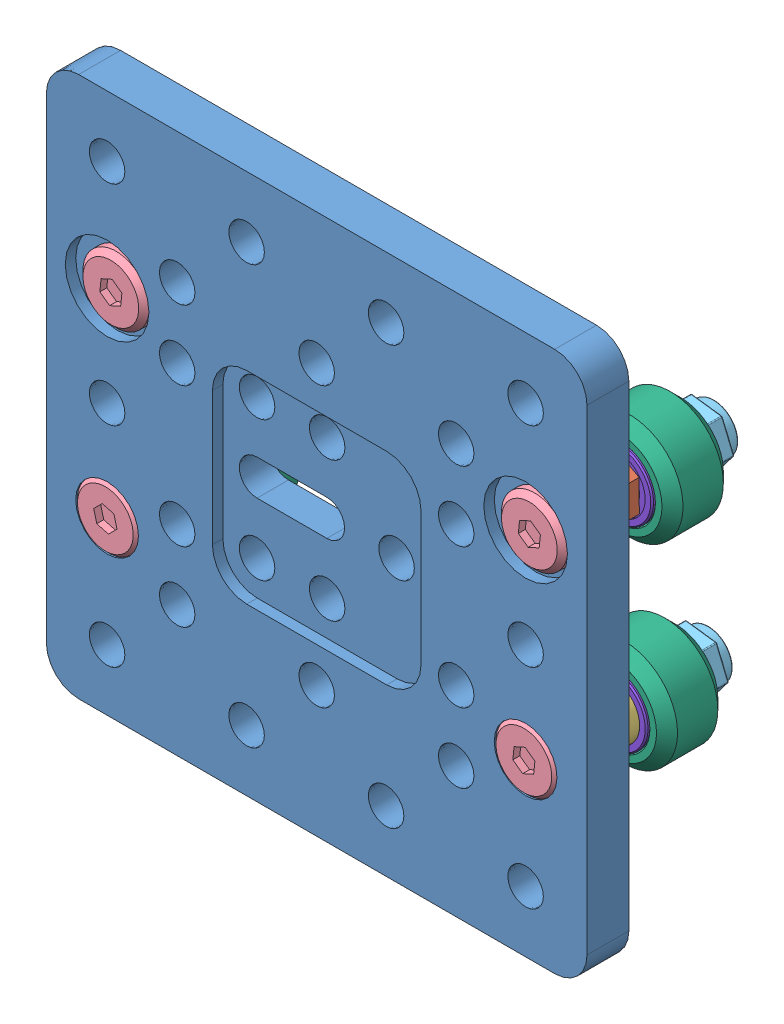
SolidWorks assembly gantry assem, configuration Default. Lengths in mm.
Overall size (77.51 77.52 27.2).
33 component instances, 8 part files, 23 mates.
Components (placement in the parent):
- cb gantry plate-1: cb gantry plate [Default] at (32.7768 44.1711 51.95) size (77.51 77.52 6)
- Steel Eccentric Spacer-1: Steel Eccentric Spacer [Default] at (2.7268 58.4216 51.95) x (0 0 -1) z (1 0 0) size (7.62 9.09 7.9)
- .25 Inch Aluminum Spacer-1: .25 Inch Aluminum Spacer [Default] at (62.7268 29.9216 45.6) x (0 0 1) z (-0.46796 0.88375 0) size (6.35 8 8)
- Steel Eccentric Spacer-2: Steel Eccentric Spacer [Default] at (62.7268 58.4216 51.95) x (0 0 -1) z (1 0 0) size (7.62 9.09 7.9)
- .25 Inch Aluminum Spacer-2: .25 Inch Aluminum Spacer [Default] at (2.7268 29.9216 45.6) x (0 0 1) z (-0.46796 0.88375 0) size (6.35 8 8)
- 5mm Low Profile Socket Head Screw - Multiple Lengths-1: 5mm Low Profile Socket Head Screw - Multiple Lengths [Default] at (62.7268 29.9216 58.2) x (0 0 -1) z (0.994788 -0.101967 0) size (27.2 9.5 9.5)
- 5mm Low Profile Socket Head Screw - Multiple Lengths-2: 5mm Low Profile Socket Head Screw - Multiple Lengths [Default] at (63.5168 58.4216 58.2) x (0 0 -1) z (0.994788 -0.101967 0) size (27.2 9.5 9.5)
- 5mm Low Profile Socket Head Screw - Multiple Lengths-3: 5mm Low Profile Socket Head Screw - Multiple Lengths [Default] at (3.5168 58.4216 58.2) x (0 0 -1) z (0.994788 -0.101967 0) size (27.2 9.5 9.5)
- 5mm Low Profile Socket Head Screw - Multiple Lengths-4: 5mm Low Profile Socket Head Screw - Multiple Lengths [Default] at (2.7268 29.9216 58.2) x (0 0 -1) z (0.966493 0.256693 0) size (27.2 9.5 9.5)
- Nylon Insert Hex Locknut 5mm-1: Nylon Insert Hex Locknut 5mm [Default] at (3.5168 58.4216 36.2) x (-0.923728 -0.383049 0) z (0 0 -1) size (7.68 8.82 4.5)
- Nylon Insert Hex Locknut 5mm-2: Nylon Insert Hex Locknut 5mm [Default] at (62.7268 29.9216 36.2) x (-0.923728 -0.383049 0) z (0 0 -1) size (7.68 8.82 4.5)
- Nylon Insert Hex Locknut 5mm-3: Nylon Insert Hex Locknut 5mm [Default] at (63.5168 58.4216 36.2) x (-0.923728 -0.383049 0) z (0 0 -1) size (7.68 8.82 4.5)
- Nylon Insert Hex Locknut 5mm-4: Nylon Insert Hex Locknut 5mm [Default] at (2.7268 29.9216 36.2) x (-0.923728 -0.383049 0) z (0 0 -1) size (7.68 8.82 4.5)
- MINI WHEEL ASSEM-1: MINI WHEEL ASSEM [Default] at (58.81 21.8771 28.3423) size (15.23 15.23 9.4)
  - Delrin Micro V-Wheel-1: Delrin Micro V-Wheel [Default] at (3.9169 8.0444 12.5577) size (15.23 15.23 8.8)
  - Micro V Precision Shim-1: Micro V Precision Shim [Default] at (3.9169 8.0444 12.0577) x (0 0 1) z (-1 0 0) size (1 8 8)
  - Mini Ball Bearing-3: Mini Ball Bearing [Default] at (3.9169 8.0444 9.9577) x (0 0 1) z (-1 0 0) size (4.2 10 10)
  - Mini Ball Bearing-4: Mini Ball Bearing [Default] at (3.9169 8.0444 15.1577) x (0 0 -1) z (0.923728 0.383049 0) size (4.2 10 10)
- MINI WHEEL ASSEM-2: MINI WHEEL ASSEM [Default] at (59.6 50.3771 28.3423) size (15.23 15.23 9.4)
  - Delrin Micro V-Wheel-1: Delrin Micro V-Wheel [Default] at (3.9169 8.0444 12.5577) size (15.23 15.23 8.8)
  - Micro V Precision Shim-1: Micro V Precision Shim [Default] at (3.9169 8.0444 12.0577) x (0 0 1) z (-1 0 0) size (1 8 8)
  - Mini Ball Bearing-3: Mini Ball Bearing [Default] at (3.9169 8.0444 9.9577) x (0 0 1) z (-1 0 0) size (4.2 10 10)
  - Mini Ball Bearing-4: Mini Ball Bearing [Default] at (3.9169 8.0444 15.1577) x (0 0 -1) z (0.923728 0.383049 0) size (4.2 10 10)
- MINI WHEEL ASSEM-3: MINI WHEEL ASSEM [Default] at (-1.19 21.8771 28.3423) size (15.23 15.23 9.4)
  - Delrin Micro V-Wheel-1: Delrin Micro V-Wheel [Default] at (3.9169 8.0444 12.5577) size (15.23 15.23 8.8)
  - Micro V Precision Shim-1: Micro V Precision Shim [Default] at (3.9169 8.0444 12.0577) x (0 0 1) z (-1 0 0) size (1 8 8)
  - Mini Ball Bearing-3: Mini Ball Bearing [Default] at (3.9169 8.0444 9.9577) x (0 0 1) z (-1 0 0) size (4.2 10 10)
  - Mini Ball Bearing-4: Mini Ball Bearing [Default] at (3.9169 8.0444 15.1577) x (0 0 -1) z (0.923728 0.383049 0) size (4.2 10 10)
- MINI WHEEL ASSEM-4: MINI WHEEL ASSEM [Default] at (-0.4 50.3771 28.3423) size (15.23 15.23 9.4)
  - Delrin Micro V-Wheel-1: Delrin Micro V-Wheel [Default] at (3.9169 8.0444 12.5577) size (15.23 15.23 8.8)
  - Micro V Precision Shim-1: Micro V Precision Shim [Default] at (3.9169 8.0444 12.0577) x (0 0 1) z (-1 0 0) size (1 8 8)
  - Mini Ball Bearing-3: Mini Ball Bearing [Default] at (3.9169 8.0444 9.9577) x (0 0 1) z (-1 0 0) size (4.2 10 10)
  - Mini Ball Bearing-4: Mini Ball Bearing [Default] at (3.9169 8.0444 15.1577) x (0 0 -1) z (0.923728 0.383049 0) size (4.2 10 10)
Mates (geometry in assembly coordinates):
- Concentric1: concentric anti-aligned: cylinder of cb gantry plate-1 through (2.7268 58.4216 51.95) axis (0 0 1) radius 3.6; cylinder of Steel Eccentric Spacer-1 through (2.7268 58.4216 53.22) axis (0 0 -1) radius 3.57
- Coincident1: coincident anti-aligned: plane of cb gantry plate-1 through (32.7768 44.1711 51.95) normal (0 0 -1); plane of Steel Eccentric Spacer-1 through (2.7268 58.4216 51.95) normal (0 0 1)
- Concentric3: concentric aligned: cylinder of cb gantry plate-1 through (62.7268 29.9216 57.95) axis (0 0 -1) radius 2.55; cylinder of .25 Inch Aluminum Spacer-1 through (62.7268 29.9216 51.95) axis (0 0 -1) radius 2.65
- Coincident3: coincident anti-aligned: plane of cb gantry plate-1 through (32.7768 44.1711 51.95) normal (0 0 -1); plane of .25 Inch Aluminum Spacer-1 through (62.7268 29.9216 51.95) normal (0 0 1)
- Concentric10: concentric anti-aligned: cylinder of cb gantry plate-1 through (62.7268 29.9216 57.95) axis (0 0 -1) radius 2.55; cylinder of 5mm Low Profile Socket Head Screw - Multiple Lengths-1 through (62.7268 29.9216 58.2) axis (0 0 1) radius 4.75
- Coincident10: coincident anti-aligned: plane of cb gantry plate-1 through (62.7268 29.9216 56.45) normal (0 0 1); plane of 5mm Low Profile Socket Head Screw - Multiple Lengths-1 through (62.9817 32.4085 56.45) normal (0 0 -1)
- Coincident11: coincident anti-aligned: plane of cb gantry plate-1 through (62.7268 58.4216 56.45) normal (0 0 1); plane of 5mm Low Profile Socket Head Screw - Multiple Lengths-2 through (63.7717 60.9085 56.45) normal (0 0 -1)
- Coincident12: coincident anti-aligned: plane of cb gantry plate-1 through (2.7268 58.4216 56.45) normal (0 0 1); plane of 5mm Low Profile Socket Head Screw - Multiple Lengths-3 through (3.7717 60.9085 56.45) normal (0 0 -1)
- Coincident13: coincident anti-aligned: plane of cb gantry plate-1 through (2.7268 29.9216 56.45) normal (0 0 1); plane of 5mm Low Profile Socket Head Screw - Multiple Lengths-4 through (2.0851 32.3378 56.45) normal (0 0 -1)
- Concentric18: concentric anti-aligned: cylinder of 5mm Low Profile Socket Head Screw - Multiple Lengths-2 through (63.5168 58.4216 58.2) axis (0 0 1) radius 4.75; cylinder of Nylon Insert Hex Locknut 5mm-3 through (63.5168 58.4216 34.6) axis (0 0 -1) radius 2.5
- Concentric19: concentric: cylinder of Nylon Insert Hex Locknut 5mm-2 through (62.7268 29.9216 34.6) axis (0 0 -1) radius 2.5; cylinder of MINI WHEEL ASSEM-1/Mini Ball Bearing-3 through (62.7268 29.9216 36.2) axis (0 0 1) radius 2.5
- Coincident18: coincident anti-aligned: plane of .25 Inch Aluminum Spacer-1 through (62.7268 29.9216 45.6) normal (0 0 -1); plane of MINI WHEEL ASSEM-1/Mini Ball Bearing-4 through (62.7268 29.9216 45.6) normal (0 0 1)
- Coincident19: coincident anti-aligned: plane of Steel Eccentric Spacer-2 through (62.7268 58.4216 45.6) normal (0 0 -1); plane of MINI WHEEL ASSEM-2/Mini Ball Bearing-4 through (63.5168 58.4216 45.6) normal (0 0 1)
- Concentric20: concentric anti-aligned: cylinder of Nylon Insert Hex Locknut 5mm-3 through (63.5168 58.4216 34.6) axis (0 0 -1) radius 2.5; cylinder of MINI WHEEL ASSEM-2/Mini Ball Bearing-3 through (63.5168 58.4216 36.2) axis (0 0 1) radius 2.5
- Concentric21: concentric aligned: cylinder of Steel Eccentric Spacer-2 through (63.5168 58.4216 45.6) axis (0 0 1) radius 2.5; cylinder of 5mm Low Profile Socket Head Screw - Multiple Lengths-2 through (63.5168 58.4216 58.2) axis (0 0 1) radius 4.75
- Concentric22: concentric: cylinder of Nylon Insert Hex Locknut 5mm-4 through (2.7268 29.9216 34.6) axis (0 0 -1) radius 2.5; cylinder of MINI WHEEL ASSEM-3/Mini Ball Bearing-3 through (2.7268 29.9216 36.2) axis (0 0 1) radius 2.5
- Coincident20: coincident anti-aligned: plane of .25 Inch Aluminum Spacer-2 through (2.7268 29.9216 45.6) normal (0 0 -1); plane of MINI WHEEL ASSEM-3/Mini Ball Bearing-4 through (2.7268 29.9216 45.6) normal (0 0 1)
- Concentric23: concentric: cylinder of Nylon Insert Hex Locknut 5mm-1 through (3.5168 58.4216 34.6) axis (0 0 -1) radius 2.5; cylinder of MINI WHEEL ASSEM-4/Mini Ball Bearing-3 through (3.5168 58.4216 36.2) axis (0 0 1) radius 2.5
- Coincident21: coincident anti-aligned: plane of Steel Eccentric Spacer-1 through (2.7268 58.4216 45.6) normal (0 0 -1); plane of MINI WHEEL ASSEM-4/Mini Ball Bearing-4 through (3.5168 58.4216 45.6) normal (0 0 1)
- Coincident22: coincident anti-aligned: plane of Nylon Insert Hex Locknut 5mm-4 through (2.7268 29.9216 36.2) normal (0 0 1); plane of MINI WHEEL ASSEM-3/Mini Ball Bearing-3 through (2.7268 29.9216 36.2) normal (0 0 -1)
- Coincident23: coincident anti-aligned: plane of Nylon Insert Hex Locknut 5mm-1 through (3.5168 58.4216 36.2) normal (0 0 1); plane of MINI WHEEL ASSEM-4/Mini Ball Bearing-3 through (3.5168 58.4216 36.2) normal (0 0 -1)
- Coincident24: coincident anti-aligned: plane of Nylon Insert Hex Locknut 5mm-2 through (62.7268 29.9216 36.2) normal (0 0 1); plane of MINI WHEEL ASSEM-1/Mini Ball Bearing-3 through (62.7268 29.9216 36.2) normal (0 0 -1)
- Coincident25: coincident anti-aligned: plane of Nylon Insert Hex Locknut 5mm-3 through (63.5168 58.4216 36.2) normal (0 0 1); plane of MINI WHEEL ASSEM-2/Mini Ball Bearing-3 through (63.5168 58.4216 36.2) normal (0 0 -1)
